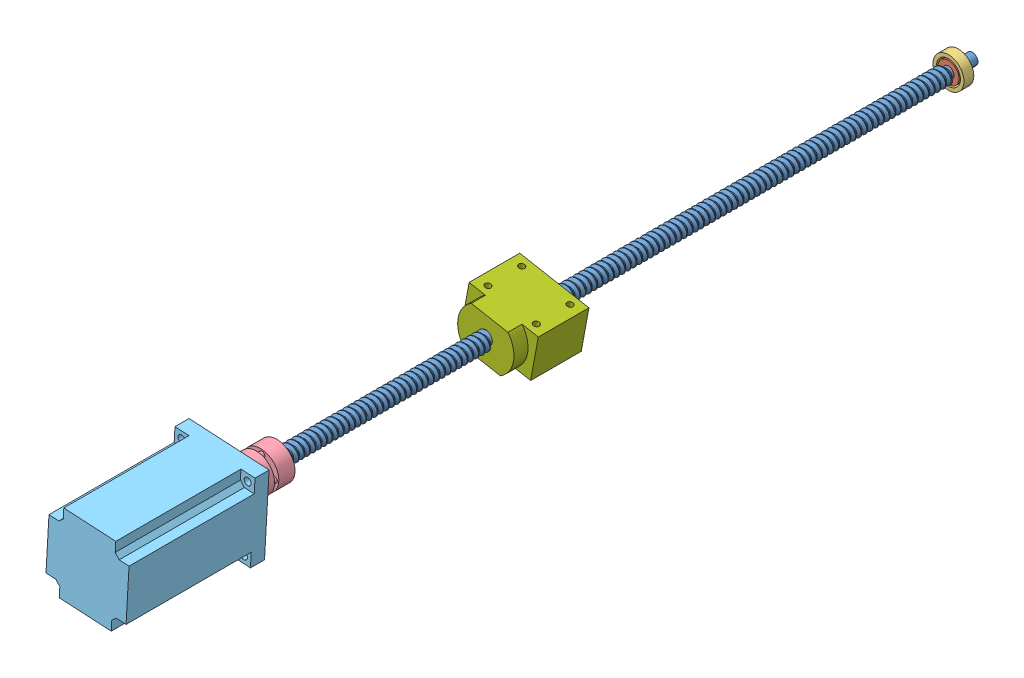
SolidWorks assembly X drive, configuration Default. Lengths in mm.
Overall size (60.15 60.15 629).
9 component instances, 7 part files, 7 mates.
Components (placement in the parent):
- X screw-1: X screw [Default] at (109.6527 -8.9932 132.9927) x (0 0 1) z (-0.999435 0.033604 0) size (506 14 12.14)
- 608 bearing-1: 608 bearing [Default] at (98.4609 -19.3648 -122.5346) x (-0.639932 -0.768431 0) z (0 0 1) size (22 22 7) (flexible)
  - inner race-1: inner race [Default] at (-10.3949 5.6455 9.7773) x (-0.344986 -0.938608 0) z (0 0 1) size (15 15 7)
  - outer race-1: outer race [Default] at (-10.3949 5.6455 9.7773) size (22 22 7)
- coupling WQ-C26L26-1: coupling WQ-C26L26 [Default] at (109.451 -14.9898 386.2427) x (0.108114 0.994139 0) z (0 0 1) size (26 26 26)
- 57 stepper motor-1: 57 stepper motor [Default] at (165.5663 -39.6064 373.5397) x (0.056863 0.998382 0) z (0 0 1) size (57 57 120) (flexible)
  - motor body-1: motor body [Default] at (21.3859 57.4242 33.703) size (57 57 100.6)
  - motor axis-1: motor axis [Default] at (21.3859 57.4242 33.703) x (-0.85154 0.52429 0) z (0 0 -1) size (8 8 21)
- screw block-1: screw block [Default] at (109.451 -14.9898 177.1145) x (0.983494 -0.180939 0) z (0 0 1) size (50 30 47.5)
Mates (geometry in assembly coordinates):
- Concentric1: concentric anti-aligned: cylinder of X screw-1 through (109.451 -14.9898 383.2427) axis (0 0 1) radius 4; cylinder of 608 bearing-1/inner race-1 through (109.451 -14.9898 -105.7573) axis (0 0 -1) radius 4
- Distance1: distance = 10 mm aligned: plane of X screw-1 through (109.6527 -8.9932 -122.7573) normal (0 0 -1); plane of 608 bearing-1/inner race-1 through (109.451 -14.9898 -112.7573) normal (0 0 -1)
- Concentric5: concentric aligned: cylinder of X screw-1 through (109.451 -14.9898 383.2427) axis (0 0 1) radius 4; cylinder of coupling WQ-C26L26-1 through (109.451 -14.9898 371.7427) axis (0 0 1) radius 13
- Coincident15: coincident aligned: plane of X screw-1 through (109.6527 -8.9932 383.2427) normal (0 0 1); plane of coupling WQ-C26L26-1 through (109.451 -14.9898 383.2427) normal (0 0 1)
- Coincident21: coincident aligned: plane of coupling WQ-C26L26-1 through (109.451 -14.9898 386.2427) normal (0 0 -1); plane of 57 stepper motor-1/motor axis-1 through (109.451 -14.9898 386.2427) normal (0 0 -1)
- Concentric22: concentric anti-aligned: cylinder of coupling WQ-C26L26-1 through (109.451 -14.9898 397.7427) axis (0 0 -1) radius 4; cylinder of 57 stepper motor-1/motor axis-1 through (109.451 -14.9898 386.2427) axis (0 0 1) radius 4
- Screw1: screw = 1 anti-aligned: cylinder of X screw-1 through (109.451 -14.9898 383.2427) axis (0 0 1) radius 6; cylinder of screw block-1 through (109.451 -14.9898 213.1145) axis (0 0 -1) radius 6
